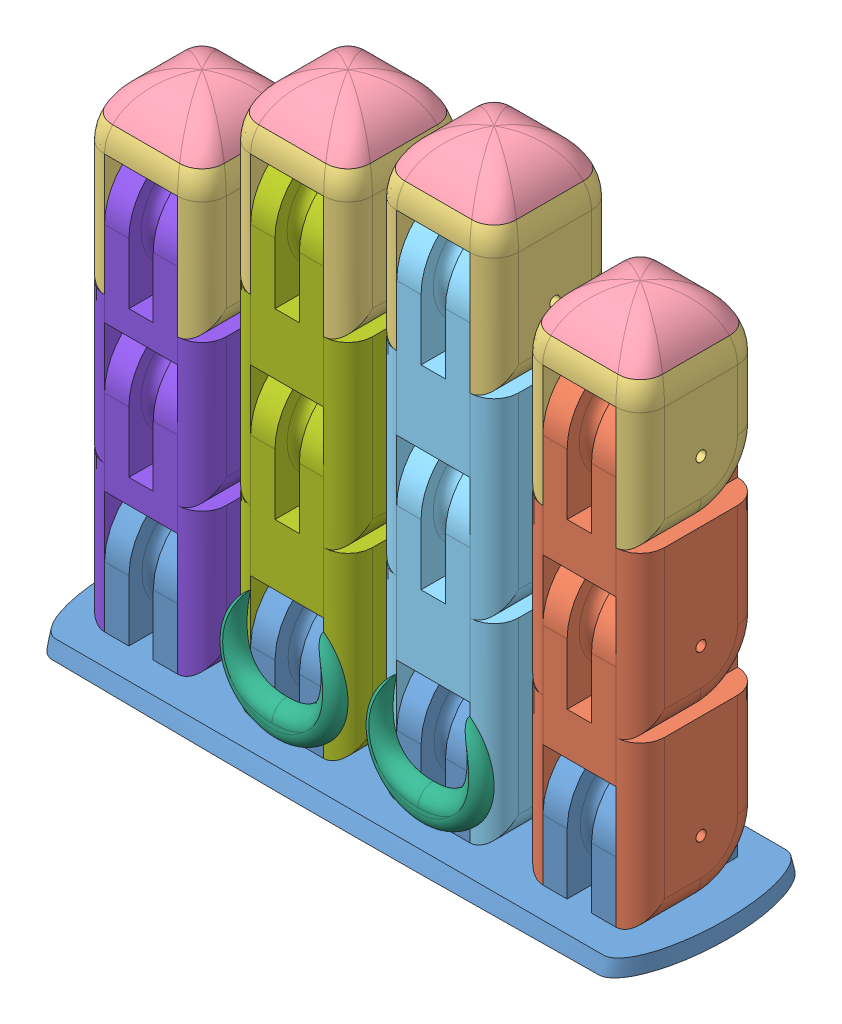
SolidWorks assembly Finger and Lid Assembly, configuration Default. Lengths in mm.
Overall size (104.96 97.49 36.85).
23 component instances, 8 part files, 12 mates.
Components (placement in the parent):
- Hand Lid-1: Hand Lid [Default] at (35.0387 -46.573 86.622) size (104.96 23.49 36.85)
- Finger Assembly 2-1: Finger Assembly 2 [Default] at (62.9609 39.05 43.1895) size (20 84 20)
  - Finger Body 2-1: Finger Body 2 [Default] at (8.0779 21.877 43.4324) size (20 47 20)
  - Finger Body 2-2: Finger Body 2 [Default] at (8.0779 48.877 43.4324) size (20 47 20)
  - Finger Top-1: Finger Top [Default] at (8.0779 75.877 43.4324) size (20 24 20)
  - Finger Tip-1: Finger Tip [Default] at (8.0779 75.877 43.4324) size (18.77 6 18.77)
- Finger Assembly 3-1: Finger Assembly 3 [Default] at (38.9609 39.05 43.1895) size (20 94 23.03)
  - Finger Body 3-1: Finger Body 3 [Default] at (8.0779 21.877 43.4324) size (20 52 20)
  - Finger Body 3-2: Finger Body 3 [Default] at (8.0779 53.877 43.4324) size (20 52 20)
  - Finger Top-1: Finger Top [Default] at (8.0779 85.877 43.4324) size (20 24 20)
  - Finger Tip-1: Finger Tip [Default] at (8.0779 85.877 43.4324) size (18.77 6 18.77)
  - Finger Moon-1: Finger Moon [Default] at (8.0779 11.877 53.4324) x (1 0 0) z (0 -1 0) size (20 3.57 18.53)
- Finger Assembly 4-1: Finger Assembly 4 [Default] at (14.9609 39.05 43.1895) size (20 90 23.03)
  - Finger Body 4-1: Finger Body 4 [Default] at (8.0779 21.877 43.4324) size (20 50 20)
  - Finger Body 4-2: Finger Body 4 [Default] at (8.0779 51.877 43.4324) size (20 50 20)
  - Finger Top-1: Finger Top [Default] at (8.0779 81.877 43.4324) size (20 24 20)
  - Finger Tip-1: Finger Tip [Default] at (8.0779 81.877 43.4324) size (18.77 6 18.77)
  - Finger Moon-1: Finger Moon [Default] at (8.0779 11.877 53.4324) x (1 0 0) z (0 -1 0) size (20 3.57 18.53)
- Finger Assembly 5-1: Finger Assembly 5 [Default] at (-9.0391 39.05 43.1895) size (20 78 20)
  - Finger Body 5-1: Finger Body 5 [Default] at (8.0779 21.877 43.4324) size (20 44 20)
  - Finger Body 5-2: Finger Body 5 [Default] at (8.0779 45.877 43.4324) size (20 44 20)
  - Finger Top-1: Finger Top [Default] at (8.0779 69.877 43.4324) size (20 24 20)
  - Finger Tip-1: Finger Tip [Default] at (8.0779 69.877 43.4324) size (18.77 6 18.77)
Mates (geometry in assembly coordinates):
- Coincident1: coincident anti-aligned: plane of Hand Lid-1 through (77.0387 50.927 76.622) normal (1 0 0); plane of Finger Assembly 2-1/Finger Body 2-1 through (77.0387 50.927 76.622) normal (-1 0 0)
- Concentric1: concentric aligned: circle of Hand Lid-1; circle of Finger Assembly 2-1/Finger Body 2-1
- LimitAngle2: limit planar angle = 1.570796 rad aligned: plane of Finger Assembly 2-1/Finger Body 2-1 through (61.0387 67.927 76.622) normal (0 0 -1); plane of Hand Lid-1 through (-9.9613 40.927 86.622) normal (0 1 0)
- Coincident4: coincident anti-aligned: plane of Hand Lid-1 through (41.0387 50.927 76.622) normal (-1 0 0); plane of Finger Assembly 3-1/Finger Body 3-1 through (41.0387 50.927 96.622) normal (1 0 0)
- Concentric2: concentric aligned: circle of Hand Lid-1; circle of Finger Assembly 3-1/Finger Body 3-1
- LimitAngle3: limit planar angle = 1.570796 rad aligned: plane of Finger Assembly 3-1/Finger Body 3-1 through (37.0387 72.927 76.622) normal (0 0 -1); plane of Hand Lid-1 through (-9.9613 40.927 86.622) normal (0 1 0)
- Coincident6: coincident anti-aligned: plane of Hand Lid-1 through (17.0387 50.927 76.622) normal (-1 0 0); plane of Finger Assembly 4-1/Finger Body 4-1 through (17.0387 50.927 96.622) normal (1 0 0)
- Concentric3: concentric aligned: circle of Hand Lid-1; circle of Finger Assembly 4-1/Finger Body 4-1
- LimitAngle4: limit planar angle = 1.570796 rad aligned: plane of Finger Assembly 4-1/Finger Body 4-1 through (13.0387 70.927 76.622) normal (0 0 -1); plane of Hand Lid-1 through (-9.9613 40.927 86.622) normal (0 1 0)
- Coincident8: coincident anti-aligned: plane of Hand Lid-1 through (-6.9613 50.927 76.622) normal (-1 0 0); plane of Finger Assembly 5-1/Finger Body 5-1 through (-6.9613 50.927 96.622) normal (1 0 0)
- Concentric4: concentric aligned: circle of Hand Lid-1; circle of Finger Assembly 5-1/Finger Body 5-1
- LimitAngle5: limit planar angle = 1.570796 rad aligned: plane of Finger Assembly 5-1/Finger Body 5-1 through (-10.9613 64.927 76.622) normal (0 0 -1); plane of Hand Lid-1 through (-9.9613 40.927 86.622) normal (0 1 0)
